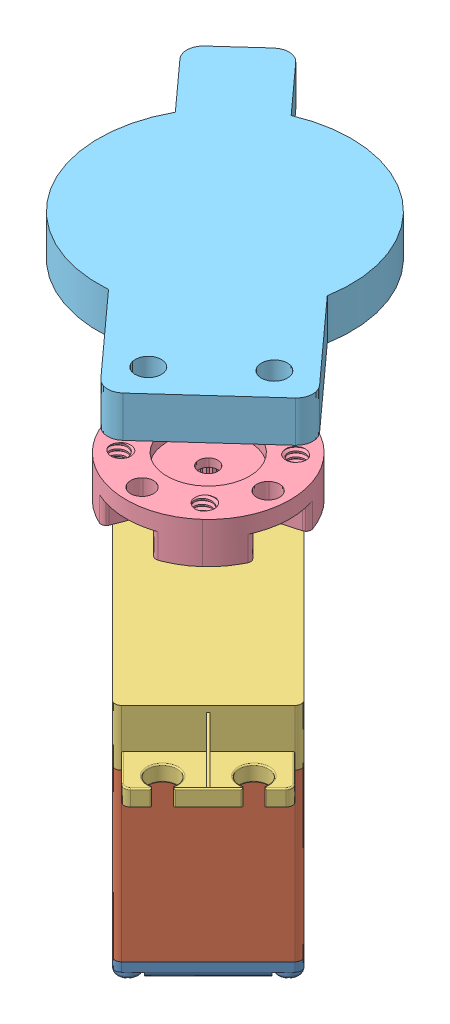
SolidWorks assembly MS-SA-0012b-Cap Release Mech Assembly, configuration Default. Lengths in mm.
Overall size (94.81 122.24 98.2).
9 component instances, 8 part files, 11 mates.
Components (placement in the parent):
- MS-P-0088-Cap Tube-1: MS-P-0088-Cap Tube [Default] at (31.5924 -20.8089 252.4544) size (117.44 117.98 108.34) (hidden)
- 11886-1: 11886 [Default] at (67.4637 37.1296 285.183) x (-0.707107 0 0.707107) z (-0.707107 0 -0.707107) size (21 45.43 55.5)
  - 11886_bottom-1: 11886_bottom [Default] at (2.2223 -4.2785 0.9275) size (21 2.43 41.5)
  - 11886_middle-1: 11886_middle [Default] at (2.2223 -1.8785 0.9275) size (21 25.7 42.9)
  - 11886_upper-1: 11886_upper [Default] at (6.1473 23.8215 -5.3225) size (21 8.72 55.5)
  - 11886_top-1: 11886_top [Default] at (2.2223 32.5215 0.7275) size (20 8.6 36.5) (hidden)
- 525130.step-1: 525130.step [Default] at (57.6351 74.9491 278.4971) x (-0.741287 0 0.671188) z (-0.671188 0 -0.741287) size (25.39 6.35 25.39)
- MS-P-0087-Cap-1: MS-P-0087-Cap [Default] at (32.9153 81.2991 251.1957) x (-0.741287 0 0.671188) z (0 1 0) size (39.12 66.19 6.35)
- MS-P-0080 Jordan Torpedo 2, 1 in-1: MS-P-0080 Jordan Torpedo 2, 1 in [Default] at (31.5924 34.4468 252.4544) x (0 1 0) z (-0.999213 0 -0.039674) size (122.24 25.4 25.4)
Mates (geometry in assembly coordinates):
- Concentric1: concentric anti-aligned: circle of 11886-1/11886_top-1; circle of 525130.step-1
- Coincident1: coincident anti-aligned: plane of 11886-1/11886_top-1 through (62.1687 78.2511 273.9636) normal (0 1 0); plane of 525130.step-1 through (57.6351 78.2511 278.4971) normal (0 -1 0)
- Coincident5: coincident anti-aligned: plane of MS-P-0088-Cap Tube-1 through (31.5924 81.2991 252.4544) normal (0 1 0); plane of MS-P-0087-Cap-1 through (32.9153 81.2991 251.1957) normal (0 -1 0)
- Concentric2: concentric anti-aligned: circle of MS-P-0087-Cap-1; circle of 525130.step-1
- Concentric3: concentric anti-aligned: cylinder of MS-P-0087-Cap-1 through (47.8681 87.6491 278.0124) axis (0 -1 0) radius 2.032; circle of 525130.step-1
- Coincident2: coincident anti-aligned: plane of MS-P-0088-Cap Tube-1 through (31.5924 81.2991 252.4544) normal (0 1 0); plane of MS-P-0087-Cap-1 through (32.9153 81.2991 251.1957) normal (0 -1 0)
- Coincident4: coincident anti-aligned: plane of 525130.step-1 through (57.6351 81.2991 278.4971) normal (0 1 0); plane of MS-P-0087-Cap-1 through (32.9153 81.2991 251.1957) normal (0 -1 0)
- Parallel5: parallel anti-aligned: line of 11886-1/11886_top-1 through (68.9488 71.9011 301.1246) axis (0.707107 0 -0.707107); line of MS-P-0088-Cap Tube-1 through (97.8666 60.9511 294.8412) axis (-0.707107 0 0.707107)
- Parallel8: parallel anti-aligned: plane of 11886-1/11886_middle-1 through (43.1394 60.9511 278.8507) normal (-0.707107 0 -0.707107); plane of MS-P-0088-Cap Tube-1 through (85.9229 -20.8089 306.7849) normal (0.707107 0 0.707107)
- Concentric4: concentric anti-aligned: cylinder of MS-P-0088-Cap Tube-1 through (86.6972 -20.8099 300.4882) axis (0 1 0) radius 2.3559; cylinder of 11886-1/11886_upper-1 through (86.6972 69.6511 300.4882) axis (0 -1 0) radius 2.25
- Concentric5: concentric aligned: circle of MS-P-0088-Cap Tube-1; circle of MS-P-0080 Jordan Torpedo 2, 1 in-1
